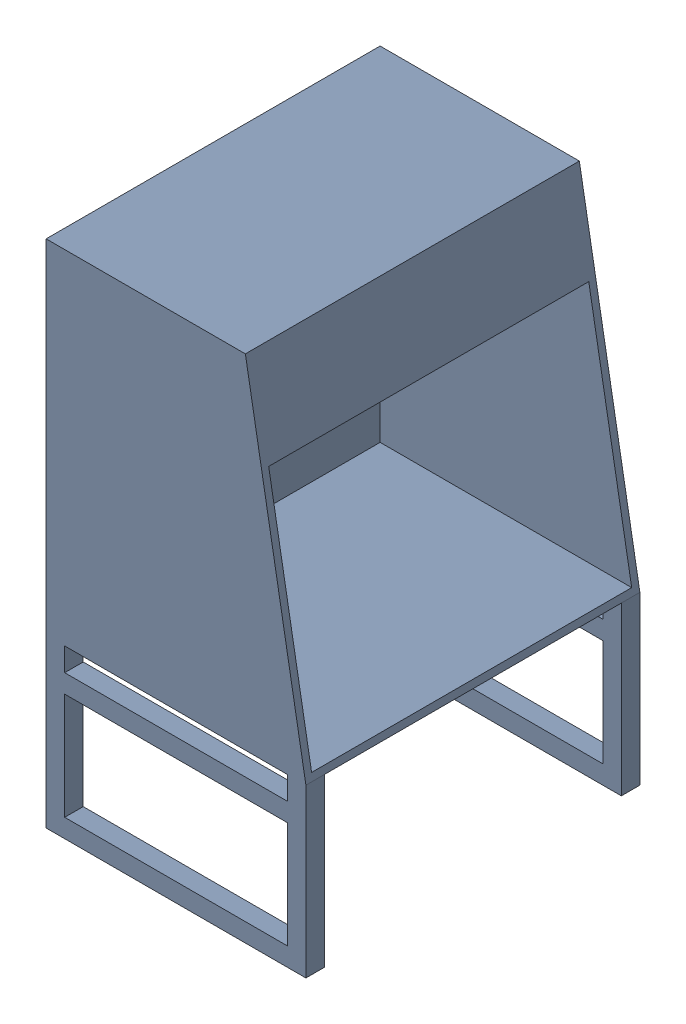
SolidWorks assembly potential design, configuration Default. Lengths in mm.
Overall size (883.2 1397 914.4).
2 component instances, 2 part files, 2 mates.
Components (placement in the parent):
- very rough bsc2 mockup-1: very rough bsc2 mockup [Default] at (60.7065 644.4737 805.9376) size (711.2 1397 914.4)
- Screen-1: Screen [Default] at (-1.2935 810.5237 1623.6808) x (0 0 -1) z (1 0 0) size (721.5 440.75 172)
Mates (geometry in assembly coordinates):
- Coincident5: coincident anti-aligned: plane of very rough bsc2 mockup-1 through (60.7065 644.4737 1720.3376) normal (-1 0 0); plane of Screen-1 through (60.7065 810.5237 1623.6808) normal (1 0 0)
- Coincident6: coincident anti-aligned: line of very rough bsc2 mockup-1 through (60.7065 838.5237 1611.3376) axis (0 0 -1); line of Screen-1 through (60.7065 838.5237 903.6808) axis (0 0 1)
